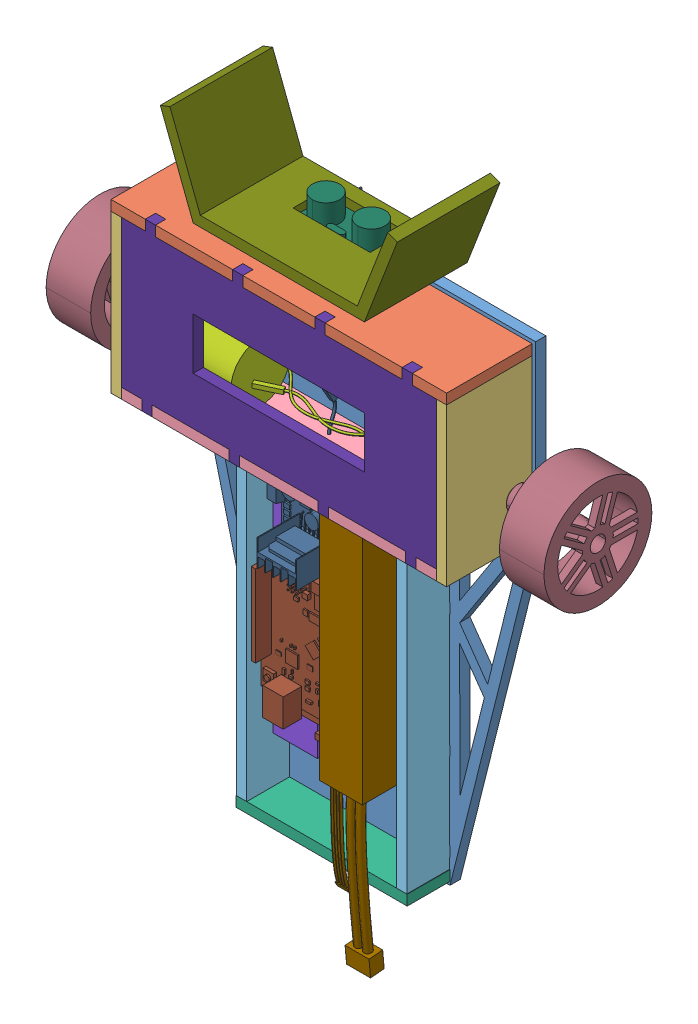
SolidWorks assembly revised, configuration 기본. Lengths in mm.
Overall size (290.8 392.49 151.94).
22 component instances, 17 part files, 36 mates.
Components (placement in the parent):
- bottom-1: bottom [기본] at (17.9171 -162.0104 297) size (200 300 6)
- frontWall-1: frontWall [기본] at (17.9171 129.9896 303) size (196 6 151.94)
- sideWall x2-1: sideWall x2 [기본] at (109.9171 83.9896 303) x (0 -1 0) z (0 0 1) size (92 6 56)
- sideWall x2-2: sideWall x2 [기본] at (-80.0829 83.9896 303) x (0 -1 0) z (0 0 1) size (92 6 56)
- midWall-1: midWall [기본] at (17.9171 43.9896 303) x (1 0 0) z (0 -1 0) size (184 56 6)
- midWall_2 x2-1: midWall_2 x2 [기본] at (61.6659 -58.0104 303) x (0 -1 0) z (0 0 1) size (192 6 31)
- midWall_2 x2-2: midWall_2 x2 [기본] at (-25.8316 -58.0104 303) x (0 1 0) z (0 0 1) size (192 6 31)
- backWall-1: backWall [기본] at (17.9171 -160.0104 303) size (100 6 31)
- motor.step-1: motor.step [기본] at (-22.6829 62.5396 323.0909) x (0 -0.999178 -0.040541) z (0 0.040541 -0.999178) size (37.1 151.83 37.1)
- motor.step-2: motor.step [기본] at (58.5171 62.5396 323.0909) x (0 0.999178 0.040541) z (0 0.040541 -0.999178) size (37.1 151.83 37.1)
- breadboard.step-1: breadboard.step [기본] at (1.1684 -44.5104 303) x (1 0 0) z (0 -1 0) size (54 9.6 165)
- lipo-battery.stp-1: lipo-battery.stp [기본] at (36.6659 211.7279 618.3149) x (0 0 1) z (1 0 0) size (45 230.34 25)
- motorcontroler.step-1: motorcontroler.step [기본] at (2.0184 -0.8795 312.6) x (1 0 0) z (0 -1 0) size (55.7 26.71 104.61)
- arduino-UNO.step-1: arduino-UNO.step [기본] at (2.5393 -66.9971 312.6) x (1 0 0) z (0 -1 0) size (57.5 18.3 80.7)
- front-wheel.stp-1: front-wheel.stp [기본] at (453.7222 -382.8089 285) size (16 22 15.01)
- wheel-basic.step-1: wheel-basic.step [기본] at (-127.4829 62.9896 312) x (0 -1 0) z (0 0 1) size (63 46.5 63)
- wheel-basic.step-2: wheel-basic.step [기본] at (163.3171 62.9896 312) x (0 1 0) z (0 0 1) size (63 46.5 63)
- infrared-sensor.step-1: infrared-sensor.step [기본] at (-7.1329 128.4446 292.35) x (-1 0 0) z (0 -1 0) size (14.1 16.75 36)
- ultrasonic-sensor.step-1: ultrasonic-sensor.step [기본] at (17.7671 147.9896 312.0191) x (-1 0 0) z (0 0 -1) size (45.3 18.15 26.45)
- infrared-sensor.step-2: infrared-sensor.step [기본] at (42.9671 128.4446 292.35) x (-1 0 0) z (0 -1 0) size (14.1 16.75 36)
- Grabber-1: Grabber [기본] at (17.9171 147.9896 293) size (138.41 70.15 60)
- topCover-1: topCover [기본] at (17.9171 43.9896 347) size (184 98 6)
Mates (geometry in assembly coordinates):
- Coincident1: coincident anti-aligned: plane of bottom-1 through (17.9171 -162.0104 303) normal (0 0 1); plane of frontWall-1 through (17.9171 129.9896 303) normal (0 0 -1)
- Coincident2: coincident anti-aligned: plane of bottom-1 through (109.9171 135.9896 303) normal (-1 0 0); plane of frontWall-1 through (109.9171 129.9896 297) normal (1 0 0)
- Coincident3: coincident anti-aligned: plane of bottom-1 through (58.9171 129.9896 303) normal (0 1 0); plane of frontWall-1 through (115.9171 129.9896 353) normal (0 -1 0)
- Coincident4: coincident anti-aligned: plane of bottom-1 through (17.9171 -162.0104 303) normal (0 0 1); plane of sideWall x2-1 through (109.9171 83.9896 303) normal (0 0 -1)
- Coincident5: coincident anti-aligned: plane of bottom-1 through (109.9171 47.9896 303) normal (1 0 0); plane of sideWall x2-1 through (109.9171 129.9896 353) normal (-1 0 0)
- Coincident6: coincident anti-aligned: plane of bottom-1 through (109.9171 119.9896 303) normal (0 -1 0); plane of sideWall x2-1 through (109.9171 119.9896 297) normal (0 1 0)
- Coincident7: coincident anti-aligned: plane of bottom-1 through (17.9171 -162.0104 303) normal (0 0 1); plane of sideWall x2-2 through (-80.0829 83.9896 303) normal (0 0 -1)
- Coincident8: coincident anti-aligned: plane of bottom-1 through (-74.0829 113.9896 303) normal (-1 0 0); plane of sideWall x2-2 through (-74.0829 129.9896 353) normal (1 0 0)
- Coincident9: coincident anti-aligned: plane of bottom-1 through (-74.0829 119.9896 303) normal (0 -1 0); plane of sideWall x2-2 through (-80.0829 119.9896 297) normal (0 1 0)
- Coincident10: coincident anti-aligned: plane of bottom-1 through (17.9171 -162.0104 303) normal (0 0 1); plane of midWall-1 through (109.9171 37.9896 303) normal (0 0 -1)
- Coincident11: coincident anti-aligned: plane of bottom-1 through (-68.0829 43.9896 303) normal (1 0 0); plane of midWall-1 through (-68.0829 37.9896 297) normal (-1 0 0)
- Coincident12: coincident anti-aligned: plane of bottom-1 through (-62.0829 43.9896 303) normal (0 -1 0); plane of midWall-1 through (17.9171 43.9896 303) normal (0 1 0)
- Coincident13: coincident anti-aligned: plane of bottom-1 through (17.9171 -162.0104 303) normal (0 0 1); plane of backWall-1 through (17.9171 -160.0104 303) normal (0 0 -1)
- Coincident14: coincident anti-aligned: plane of bottom-1 through (29.9171 -154.0104 303) normal (0 -1 0); plane of backWall-1 through (-32.0829 -154.0104 328) normal (0 1 0)
- Coincident15: coincident anti-aligned: plane of bottom-1 through (-20.0829 -160.0104 303) normal (-1 0 0); plane of backWall-1 through (-20.0829 -160.0104 297) normal (1 0 0)
- Coincident16: coincident anti-aligned: plane of bottom-1 through (17.9171 -162.0104 303) normal (0 0 1); plane of midWall_2 x2-1 through (61.6659 -58.0104 303) normal (0 0 -1)
- Coincident17: coincident anti-aligned: plane of bottom-1 through (61.6659 31.9896 303) normal (1 0 0); plane of midWall_2 x2-1 through (61.6659 -154.0104 328) normal (-1 0 0)
- Coincident18: coincident anti-aligned: plane of bottom-1 through (61.9171 -148.0104 303) normal (0 1 0); plane of midWall_2 x2-1 through (67.6659 -148.0104 303) normal (0 -1 0)
- Coincident19: coincident anti-aligned: plane of bottom-1 through (-25.8316 31.9896 303) normal (-1 0 0); plane of midWall_2 x2-2 through (-25.8316 37.9896 328) normal (1 0 0)
- Coincident20: coincident anti-aligned: plane of bottom-1 through (-26.0829 -148.0104 303) normal (0 1 0); plane of midWall_2 x2-2 through (-31.8316 -148.0104 303) normal (0 -1 0)
- Coincident21: coincident anti-aligned: plane of bottom-1 through (17.9171 -162.0104 303) normal (0 0 1); plane of midWall_2 x2-2 through (-25.8316 -58.0104 303) normal (0 0 -1)
- Coincident32: coincident anti-aligned: plane of bottom-1 through (17.9171 -162.0104 297) normal (0 0 -1); plane of front-wheel.stp-1 through (6.2997 -127.4584 297) normal (0 0 1)
- Coincident37: coincident anti-aligned: plane of frontWall-1 through (-4.5829 135.9896 336.5) normal (1 0 0); plane of Grabber-1 through (-4.5829 129.9896 336.5) normal (-1 0 0)
- Coincident38: coincident anti-aligned: plane of frontWall-1 through (-4.5829 135.9896 330.5) normal (0 0 1); plane of Grabber-1 through (-4.5829 129.9896 330.5) normal (0 0 -1)
- Coincident39: coincident aligned: plane of frontWall-1 through (115.9171 129.9896 353) normal (0 -1 0); plane of Grabber-1 through (17.9171 129.9896 293) normal (0 -1 0)
- Coincident44: coincident anti-aligned: plane of ultrasonic-sensor.step-1 through (-4.8829 149.6396 322.1691) normal (0 0 1); plane of Grabber-1 through (-4.5829 153.9896 322.1691) normal (0 0 -1)
- Coincident45: coincident anti-aligned: plane of ultrasonic-sensor.step-1 through (40.4171 149.6396 322.1691) normal (1 0 0); plane of Grabber-1 through (40.4171 153.9896 301.1691) normal (-1 0 0)
- Coincident46: coincident aligned: plane of ultrasonic-sensor.step-1 through (17.7671 147.9896 312.0191) normal (0 -1 0); plane of Grabber-1 through (67.9171 147.9896 353) normal (0 -1 0)
- Coincident50: coincident anti-aligned: plane of midWall_2 x2-2 through (-25.8316 37.9896 328) normal (1 0 0); plane of motorcontroler.step-1 through (-25.8316 -0.8795 312.6) normal (-1 0 0)
- Coincident52: coincident anti-aligned: plane of midWall_2 x2-2 through (-25.8316 37.9896 328) normal (1 0 0); plane of arduino-UNO.step-1 through (-25.8316 -29.1773 319.6) normal (-1 0 0)
- Coincident53: coincident anti-aligned: plane of bottom-1 through (17.9171 -162.0104 297) normal (0 0 -1); plane of infrared-sensor.step-2 through (42.9671 128.4446 297) normal (0 0 1)
- Coincident55: coincident anti-aligned: plane of bottom-1 through (-82.0829 137.9896 303) normal (0 1 0); plane of infrared-sensor.step-2 through (48.4171 137.9896 282.6) normal (0 -1 0)
- Tangent3: tangent: circle of bottom-1; plane of infrared-sensor.step-2 through (35.9171 113.3446 290.65) normal (-1 0 0)
- Coincident59: coincident anti-aligned: plane of frontWall-1 through (-54.0829 129.9896 347) normal (-1 0 0); plane of topCover-1 through (-54.0829 129.9896 353) normal (1 0 0)
- Coincident60: coincident anti-aligned: plane of frontWall-1 through (-60.0829 129.9896 347) normal (0 0 1); plane of topCover-1 through (17.9171 43.9896 347) normal (0 0 -1)
- Coincident61: coincident aligned: plane of frontWall-1 through (-80.0829 135.9896 353) normal (0 1 0); plane of topCover-1 through (-54.0829 135.9896 353) normal (0 1 0)
